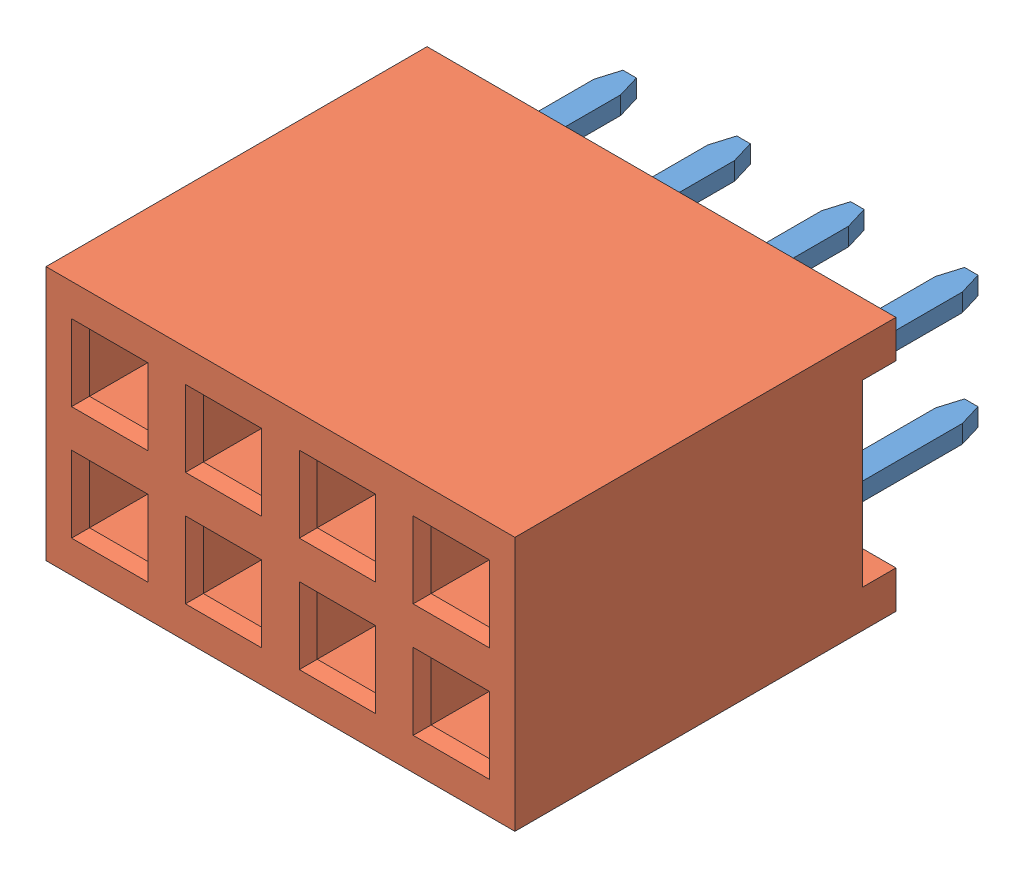
SolidWorks assembly User Library-MULTICOMP 2214S-08SG-85, configuration Default. Lengths in mm.
Overall size (10.46 5.68 11.6).
9 component instances, 2 part files, 0 mates.
Components (placement in the parent):
- User Library-MULTICOMP 2214S-08SG-85_contact-1: User Library-MULTICOMP 2214S-08SG-85_contact [Default] at (-3.81 -1.07 0.9) x (1 0 0) z (0 -1 0) size (2 10 0.4)
- User Library-MULTICOMP 2214S-08SG-85_contact-2: User Library-MULTICOMP 2214S-08SG-85_contact [Default] at (-3.81 1.47 0.9) x (1 0 0) z (0 -1 0) size (2 10 0.4)
- User Library-MULTICOMP 2214S-08SG-85_contact-3: User Library-MULTICOMP 2214S-08SG-85_contact [Default] at (-1.27 -1.07 0.9) x (1 0 0) z (0 -1 0) size (2 10 0.4)
- User Library-MULTICOMP 2214S-08SG-85_contact-4: User Library-MULTICOMP 2214S-08SG-85_contact [Default] at (-1.27 1.47 0.9) x (1 0 0) z (0 -1 0) size (2 10 0.4)
- User Library-MULTICOMP 2214S-08SG-85_contact-5: User Library-MULTICOMP 2214S-08SG-85_contact [Default] at (1.27 1.47 0.9) x (1 0 0) z (0 -1 0) size (2 10 0.4)
- User Library-MULTICOMP 2214S-08SG-85_contact-6: User Library-MULTICOMP 2214S-08SG-85_contact [Default] at (1.27 -1.07 0.9) x (1 0 0) z (0 -1 0) size (2 10 0.4)
- User Library-MULTICOMP 2214S-08SG-85_contact-7: User Library-MULTICOMP 2214S-08SG-85_contact [Default] at (3.81 -1.47 0.9) x (-1 0 0) z (0 1 0) size (2 10 0.4)
- User Library-MULTICOMP 2214S-08SG-85_contact-8: User Library-MULTICOMP 2214S-08SG-85_contact [Default] at (3.81 1.07 0.9) x (-1 0 0) z (0 1 0) size (2 10 0.4)
- User Library-MULTICOMP 2214S-08SG-85_housing-1: User Library-MULTICOMP 2214S-08SG-85_housing [Default] at origin size (10.46 5.68 8.5)
